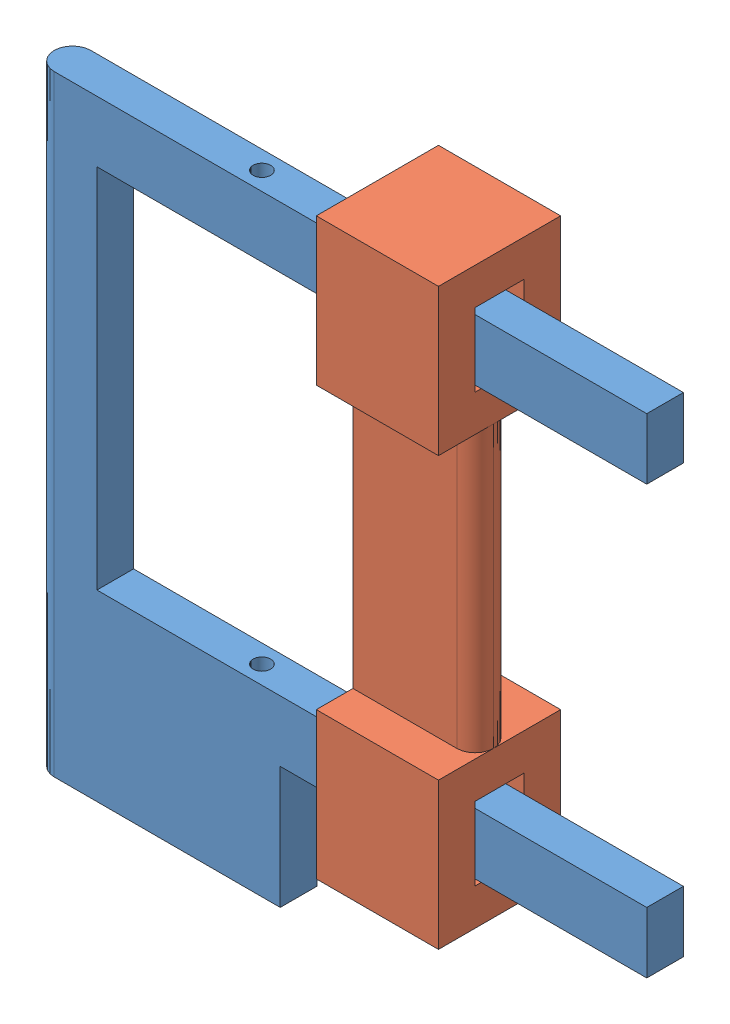
SolidWorks assembly frame_v5, configuration Default. Lengths in mm.
Overall size (25 26.75 5).
2 component instances, 2 part files, 3 mates.
Components (placement in the parent):
- frame_v5_fixed-1: frame_v5_fixed [Default] at (-0.6132 8.6275 27.4396) size (25 25 1.5)
- frame_v5_slider-1: frame_v5_slider [Default] at (12.363 9.8775 27.9396) x (0 1 0) z (1 0 0) size (23.5 5 5)
Mates (geometry in assembly coordinates):
- Coincident1: coincident anti-aligned: plane of frame_v5_fixed-1 through (-0.6132 8.6275 28.9396) normal (0 0 1); plane of frame_v5_slider-1 through (17.363 8.3775 28.9396) normal (0 0 -1)
- Distance2: distance = 0.25 mm anti-aligned: plane of frame_v5_fixed-1 through (24.3868 11.1275 28.9396) normal (0 1 0); plane of frame_v5_slider-1 through (17.363 11.3775 26.9396) normal (0 -1 0)
- LimitDistance1: limit distance = 2.9762 mm anti-aligned: plane of frame_v5_fixed-1 through (9.3868 3.6275 28.9396) normal (1 0 0); plane of frame_v5_slider-1 through (12.363 9.8775 27.9396) normal (-1 0 0)
